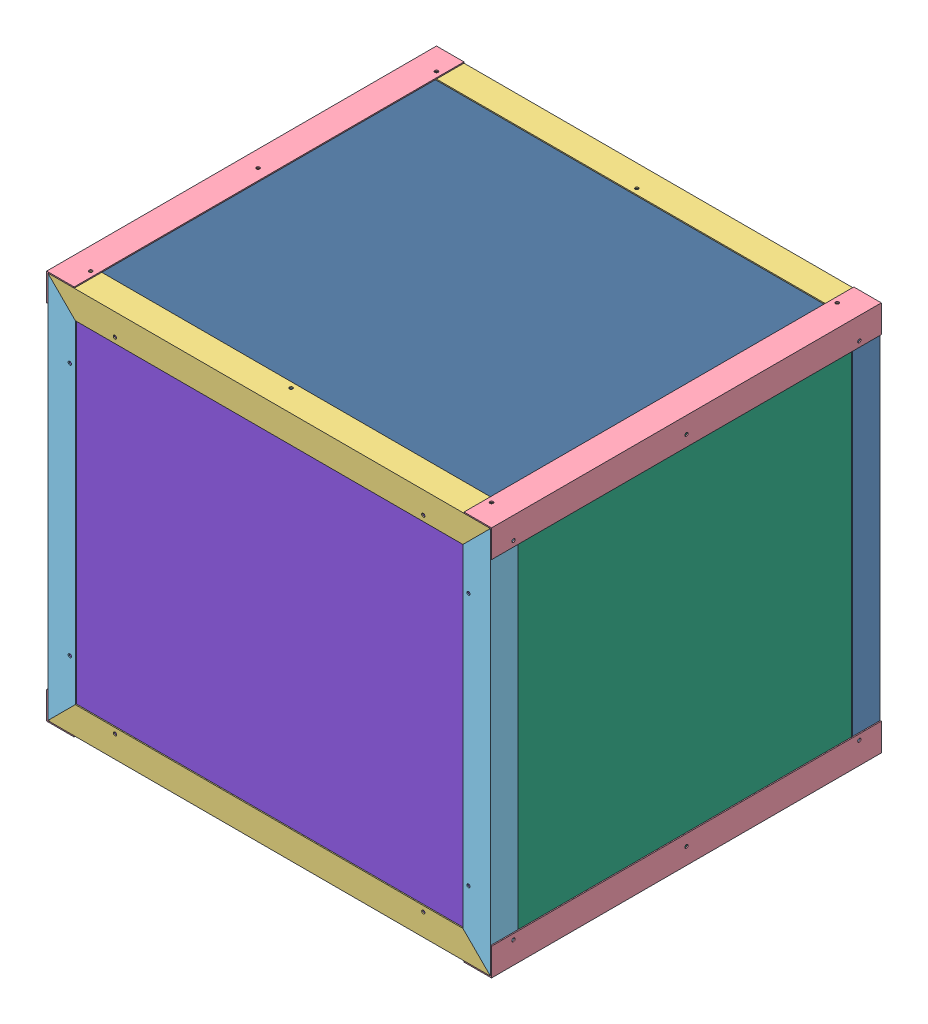
SolidWorks assembly INCUBADORA3.1, configuration Predeterminado. Lengths in mm.
Overall size (404 354 354).
34 component instances, 20 part files, 66 mates.
Components (placement in the parent):
- Soporte_Estructura_vertical_frontalIZQ_35x2.5x0.1-1: Soporte_Estructura_vertical_frontalIZQ_35x2.5x0.1 [Predeterminado] at (-68.7256 99.4418 337.5001) size (25 350 25)
- Soporte_Estructura_vertical_frontalDER_35x2.5x0.1-1: Soporte_Estructura_vertical_frontalDER_35x2.5x0.1 [Predeterminado] at (-579.6091 -128.1974 337.5001) x (-1 0 0) z (0 0 1) size (25 350 25)
- Soporte_Estructura_Horizontal_40x2.5x0.1-1: Soporte_Estructura_Horizontal_40x2.5x0.1 [Predeterminado] at (-416.987 216.064 337.5001) x (0 1 0) z (0 0 1) size (25 400 25)
- Soporte_Estructura_Horizontal_40x2.5x0.1-2: Soporte_Estructura_Horizontal_40x2.5x0.1 [Predeterminado] at (-231.3477 -244.8196 337.5001) x (0 -1 0) z (0 0 1) size (25 400 25)
- Soporte_Estructura_Esquinas_35.4x2.5x0.1-1: Soporte_Estructura_Esquinas_35.4x2.5x0.1 [Predeterminado] at (-66.9091 162.6222 626.3194) x (1 0 0) z (0 -1 0) size (25 354 25)
- Soporte_Estructura_Esquinas_35.4x2.5x0.1-2: Soporte_Estructura_Esquinas_35.4x2.5x0.1 [Predeterminado] at (-526.1674 217.8804 626.3194) x (0 1 0) z (1 0 0) size (25 354 25)
- Soporte_Estructura_Esquinas_35.4x2.5x0.1-3: Soporte_Estructura_Esquinas_35.4x2.5x0.1 [Predeterminado] at (-66.9091 -191.3778 402.6808) x (1 0 0) z (0 1 0) size (25 354 25)
- Soporte_Estructura_Esquinas_35.4x2.5x0.1-4: Soporte_Estructura_Esquinas_35.4x2.5x0.1 [Predeterminado] at (-581.4256 -191.3778 626.3194) x (-1 0 0) z (0 1 0) size (25 354 25)
- Soporte_Estructura_vertica_35x2.5x0.1-1: Soporte_Estructura_vertica_35x2.5x0.1 [Predeterminado] at (-579.6091 99.4418 691.5001) x (-1 0 0) z (0 0 -1) size (25 350 25)
- Soporte_Estructura_Horizontal_40x2.5x0.1-3: Soporte_Estructura_Horizontal_40x2.5x0.1 [Predeterminado] at (-231.3477 216.064 691.5001) x (0 1 0) z (0 0 -1) size (25 400 25)
- Soporte_Estructura_vertica_35x2.5x0.1-2: Soporte_Estructura_vertica_35x2.5x0.1 [Predeterminado] at (-68.7256 -128.1974 691.5001) x (1 0 0) z (0 0 -1) size (25 350 25)
- Soporte_Estructura_Horizontal_40x2.5x0.1-4: Soporte_Estructura_Horizontal_40x2.5x0.1 [Predeterminado] at (-416.987 -244.8196 691.5001) x (0 -1 0) z (0 0 -1) size (25 400 25)
- PVC_34x34x0.5-1: PVC_34x34x0.5 [Predeterminado] at (-524.1674 106.0862 623.4473) x (0 0 -1) z (1 0 0) size (340 340 5)
- PVC_34x34x0.5-2: PVC_34x34x0.5 [Predeterminado] at (-129.1674 106.0862 623.4473) x (0 0 -1) z (1 0 0) size (340 340 5)
- PVC_15x39x0.5-1: PVC_15x39x0.5 [Predeterminado] at (-454.5461 96.675 338.5001) x (0 1 0) z (0 0 1) size (120 390 5)
- PVC_FONDO_34x39x0.5-1: PVC_FONDO_34x39x0.5 [Predeterminado] at (-178.7034 94.5694 685.5001) x (0 -1 0) z (0 0 1) size (340 390 5)
- Soporte_Estructura_vertical_central-IZQ_35x2.5x0.1-1: Soporte_Estructura_vertical_central-IZQ_35x2.5x0.1 [Predeterminado] at (-73.8274 99.4418 502.0001) size (25 352 25)
- PVC_34x39x0.5-4: PVC_34x39x0.5 [Predeterminado] at (-178.7034 160.6222 576.1027) x (0 0 -1) z (0 -1 0) size (340 390 5)
- Soporte_Estructura_vertical_central-DER_35x2.5x0.1-2: Soporte_Estructura_vertical_central-DER_35x2.5x0.1 [Predeterminado] at (-574.5074 -128.1974 502.0001) x (-1 0 0) z (0 0 1) size (25 352 25)
- PVC_34x39x0.5-5: PVC_34x39x0.5 [Predeterminado] at (-469.6313 -189.3778 576.1027) x (0 0 -1) z (0 1 0) size (340 390 5)
- Powder Coating Oven Light Unit-1: Powder Coating Oven Light Unit [Default] at (-335.8979 98.7262 682.5791) x (-1 0 0) z (0 -1 0) size (113.79 123.2 113.79)
  - Porcelain Lampholder Light Fixture-1: Porcelain Lampholder Light Fixture [Default] at origin size (113.79 41.16 113.79)
  - Light Bulb-1: Light Bulb [Default] at (0 12.954 0) x (0.978795 0 0.204841) z (-0.204841 0 0.978795) size (60.2 107.19 60.2)
- Bandeja_Huevos_27x36x2.5-1: Bandeja_Huevos_27x36x2.5 [Predeterminado] at (-320.2845 -467.3185 590.677) x (0 -0.439591 -0.898198) z (0 0.898198 -0.439591) size (272 362 29)
  - Soporte_Bandeja_Horizonta_40x2.5x0.1-1: Soporte_Bandeja_Horizonta_40x2.5x0.1 [Predeterminado] at (53.9361 154.3977 387.5) size (25 360 25)
  - Soporte_Bandeja_Horizonta_40x2.5x0.1-4: Soporte_Bandeja_Horizonta_40x2.5x0.1 [Predeterminado] at (-274.8673 -152.6319 387.5) x (-1 0 0) z (0 0 1) size (25 360 25)
  - Soporte_Bandeja_Vertical_27x2.5x0.1-2: Soporte_Bandeja_Vertical_27x2.5x0.1 [Predeterminado] at (-218.9804 210.2846 386.5) x (0 1 0) z (0 0 1) size (25 270 25)
  - Soporte_Bandeja_Vertical_27x2.5x0.1-3: Soporte_Bandeja_Vertical_27x2.5x0.1 [Predeterminado] at (-1.9508 -208.5189 386.5) x (0 -1 0) z (0 0 1) size (25 270 25)
  - Bandeja_Down_27x36x0.5-1: Bandeja_Down_27x36x0.5 [Predeterminado] at (-199.9841 -101.0844 388.5) x (0 1 0) z (0 0 1) size (350 260 3)
  - Bandeja_Up_27x36x0.3-1: Bandeja_Up_27x36x0.3 [Predeterminado] at (-20.9471 102.8502 412.5) x (0 -1 0) z (0 0 1) size (360 270 3)
- fan-1: fan [Default] at (-334.2663 115.6222 522.7811) x (1 0 0) z (0 -1 0) size (80 25.5 80)
  - stator-1: stator [Default] at origin size (80 25.5 80)
  - rotor-1: rotor [Default] at (0 2.5 0) x (0.997026 0 -0.077067) z (0.077067 0 0.997026) size (70 23.35 70)
- 20X4LCD JHD204A-1: 20X4LCD JHD204A [Default] at (-419.5674 97.6222 346.8001) x (1 0 0) z (0 1 0) size (98.3 9.76 60)
Mates (geometry in assembly coordinates):
- Coincidente1: coincident anti-aligned: plane of Soporte_Estructura_vertical_frontalIZQ_35x2.5x0.1-1 through (-124.1674 160.6222 338.5001) normal (-0.707107 0.707107 0); plane of Soporte_Estructura_Horizontal_40x2.5x0.1-1 through (-124.1674 160.6222 338.5001) normal (0.707107 -0.707107 0)
- Coincidente2: coincident aligned: plane of Soporte_Estructura_vertical_frontalIZQ_35x2.5x0.1-1 through (-68.7256 99.4418 337.5001) normal (0 0 -1); plane of Soporte_Estructura_Horizontal_40x2.5x0.1-1 through (-416.987 216.064 337.5001) normal (0 0 -1)
- Coincidente3: coincident aligned: line of Soporte_Estructura_vertical_frontalIZQ_35x2.5x0.1-1 through (-124.1674 160.6222 362.5001) axis (0 0 -1); line of Soporte_Estructura_Horizontal_40x2.5x0.1-1 through (-124.1674 160.6222 362.5001) axis (0 0 -1)
- Coincidente4: coincident anti-aligned: plane of Soporte_Estructura_vertical_frontalDER_35x2.5x0.1-1 through (-524.1674 160.6222 338.5001) normal (0.707107 0.707107 0); plane of Soporte_Estructura_Horizontal_40x2.5x0.1-1 through (-524.1674 160.6222 338.5001) normal (-0.707107 -0.707107 0)
- Coincidente5: coincident aligned: plane of Soporte_Estructura_vertical_frontalDER_35x2.5x0.1-1 through (-579.6091 -128.1974 337.5001) normal (0 0 -1); plane of Soporte_Estructura_Horizontal_40x2.5x0.1-1 through (-416.987 216.064 337.5001) normal (0 0 -1)
- Coincidente6: coincident aligned: line of Soporte_Estructura_vertical_frontalDER_35x2.5x0.1-1 through (-524.1674 160.6222 362.5001) axis (0 0 -1); line of Soporte_Estructura_Horizontal_40x2.5x0.1-1 through (-524.1674 160.6222 362.5001) axis (0 0 -1)
- Coincidente7: coincident anti-aligned: plane of Soporte_Estructura_vertical_frontalDER_35x2.5x0.1-1 through (-524.1674 -189.3778 338.5001) normal (0.707107 -0.707107 0); plane of Soporte_Estructura_Horizontal_40x2.5x0.1-2 through (-524.1674 -189.3778 338.5001) normal (-0.707107 0.707107 0)
- Coincidente8: coincident aligned: plane of Soporte_Estructura_vertical_frontalDER_35x2.5x0.1-1 through (-579.6091 -128.1974 337.5001) normal (0 0 -1); plane of Soporte_Estructura_Horizontal_40x2.5x0.1-2 through (-231.3477 -244.8196 337.5001) normal (0 0 -1)
- Coincidente9: coincident aligned: line of Soporte_Estructura_vertical_frontalDER_35x2.5x0.1-1 through (-524.1674 -189.3778 362.5001) axis (0 0 -1); line of Soporte_Estructura_Horizontal_40x2.5x0.1-2 through (-524.1674 -189.3778 362.5001) axis (0 0 -1)
- Coincidente10: coincident anti-aligned: plane of Soporte_Estructura_Horizontal_40x2.5x0.1-1 through (-524.1674 161.6222 362.5001) normal (0 1 0); plane of Soporte_Estructura_Esquinas_35.4x2.5x0.1-1 through (-66.9091 161.6222 626.3194) normal (0 -1 0)
- Coincidente11: coincident anti-aligned: plane of Soporte_Estructura_vertical_frontalIZQ_35x2.5x0.1-1 through (-123.1674 160.6222 362.5001) normal (1 0 0); plane of Soporte_Estructura_Esquinas_35.4x2.5x0.1-1 through (-123.1674 137.6222 691.5001) normal (-1 0 0)
- Coincidente12: coincident aligned: plane of Soporte_Estructura_vertical_frontalIZQ_35x2.5x0.1-1 through (-68.7256 99.4418 337.5001) normal (0 0 -1); plane of Soporte_Estructura_Esquinas_35.4x2.5x0.1-1 through (-123.1674 137.6222 337.5001) normal (0 0 -1)
- Coincidente13: coincident anti-aligned: plane of Soporte_Estructura_Horizontal_40x2.5x0.1-1 through (-524.1674 161.6222 362.5001) normal (0 1 0); plane of Soporte_Estructura_Esquinas_35.4x2.5x0.1-2 through (-501.1674 161.6222 691.5001) normal (0 -1 0)
- Coincidente14: coincident anti-aligned: plane of Soporte_Estructura_vertical_frontalDER_35x2.5x0.1-1 through (-525.1674 -189.3778 362.5001) normal (-1 0 0); plane of Soporte_Estructura_Esquinas_35.4x2.5x0.1-2 through (-525.1674 217.8804 626.3194) normal (1 0 0)
- Coincidente16: coincident aligned: plane of Soporte_Estructura_Horizontal_40x2.5x0.1-1 through (-416.987 216.064 337.5001) normal (0 0 -1); plane of Soporte_Estructura_Esquinas_35.4x2.5x0.1-2 through (-501.1674 161.6222 337.5001) normal (0 0 -1)
- Coincidente17: coincident anti-aligned: plane of Soporte_Estructura_Horizontal_40x2.5x0.1-2 through (-124.1674 -190.3778 362.5001) normal (0 -1 0); plane of Soporte_Estructura_Esquinas_35.4x2.5x0.1-3 through (-66.9091 -190.3778 402.6808) normal (0 1 0)
- Coincidente19: coincident anti-aligned: plane of Soporte_Estructura_vertical_frontalIZQ_35x2.5x0.1-1 through (-123.1674 160.6222 362.5001) normal (1 0 0); plane of Soporte_Estructura_Esquinas_35.4x2.5x0.1-3 through (-123.1674 -166.3778 337.5001) normal (-1 0 0)
- Coincidente20: coincident aligned: plane of Soporte_Estructura_vertical_frontalIZQ_35x2.5x0.1-1 through (-68.7256 99.4418 337.5001) normal (0 0 -1); plane of Soporte_Estructura_Esquinas_35.4x2.5x0.1-3 through (-123.1674 -166.3778 337.5001) normal (0 0 -1)
- Coincidente21: coincident anti-aligned: plane of Soporte_Estructura_Horizontal_40x2.5x0.1-2 through (-124.1674 -190.3778 362.5001) normal (0 -1 0); plane of Soporte_Estructura_Esquinas_35.4x2.5x0.1-4 through (-581.4256 -190.3778 626.3194) normal (0 1 0)
- Coincidente22: coincident anti-aligned: plane of Soporte_Estructura_vertical_frontalDER_35x2.5x0.1-1 through (-525.1674 -189.3778 362.5001) normal (-1 0 0); plane of Soporte_Estructura_Esquinas_35.4x2.5x0.1-4 through (-525.1674 -166.3778 691.5001) normal (1 0 0)
- Coincidente23: coincident aligned: plane of Soporte_Estructura_vertical_frontalDER_35x2.5x0.1-1 through (-579.6091 -128.1974 337.5001) normal (0 0 -1); plane of Soporte_Estructura_Esquinas_35.4x2.5x0.1-4 through (-525.1674 -166.3778 337.5001) normal (0 0 -1)
- Coincidente24: coincident anti-aligned: plane of Soporte_Estructura_Esquinas_35.4x2.5x0.1-2 through (-525.1674 217.8804 626.3194) normal (1 0 0); plane of Soporte_Estructura_vertica_35x2.5x0.1-1 through (-525.1674 160.6222 666.5001) normal (-1 0 0)
- Coincidente25: coincident aligned: plane of Soporte_Estructura_Esquinas_35.4x2.5x0.1-2 through (-501.1674 161.6222 691.5001) normal (0 0 1); plane of Soporte_Estructura_vertica_35x2.5x0.1-1 through (-579.6091 99.4418 691.5001) normal (0 0 1)
- Coincidente27: coincident anti-aligned: plane of Soporte_Estructura_Esquinas_35.4x2.5x0.1-2 through (-501.1674 161.6222 691.5001) normal (0 -1 0); plane of Soporte_Estructura_Horizontal_40x2.5x0.1-3 through (-124.1674 161.6222 666.5001) normal (0 1 0)
- Coincidente28: coincident aligned: plane of Soporte_Estructura_vertica_35x2.5x0.1-1 through (-579.6091 99.4418 691.5001) normal (0 0 1); plane of Soporte_Estructura_Horizontal_40x2.5x0.1-3 through (-231.3477 216.064 691.5001) normal (0 0 1)
- Coincidente29: coincident anti-aligned: plane of Soporte_Estructura_vertica_35x2.5x0.1-1 through (-524.1674 160.6222 690.5001) normal (0.707107 0.707107 0); plane of Soporte_Estructura_Horizontal_40x2.5x0.1-3 through (-524.1674 160.6222 690.5001) normal (-0.707107 -0.707107 0)
- Coincidente30: coincident aligned: plane of Soporte_Estructura_Horizontal_40x2.5x0.1-3 through (-231.3477 216.064 691.5001) normal (0 0 1); plane of Soporte_Estructura_vertica_35x2.5x0.1-2 through (-68.7256 -128.1974 691.5001) normal (0 0 1)
- Coincidente31: coincident anti-aligned: plane of Soporte_Estructura_Esquinas_35.4x2.5x0.1-1 through (-123.1674 137.6222 691.5001) normal (-1 0 0); plane of Soporte_Estructura_vertica_35x2.5x0.1-2 through (-123.1674 -189.3778 666.5001) normal (1 0 0)
- Coincidente32: coincident anti-aligned: plane of Soporte_Estructura_Horizontal_40x2.5x0.1-3 through (-124.1674 160.6222 690.5001) normal (0.707107 -0.707107 0); plane of Soporte_Estructura_vertica_35x2.5x0.1-2 through (-124.1674 160.6222 690.5001) normal (-0.707107 0.707107 0)
- Coincidente33: coincident aligned: plane of Soporte_Estructura_vertica_35x2.5x0.1-2 through (-68.7256 -128.1974 691.5001) normal (0 0 1); plane of Soporte_Estructura_Horizontal_40x2.5x0.1-4 through (-416.987 -244.8196 691.5001) normal (0 0 1)
- Coincidente34: coincident anti-aligned: plane of Soporte_Estructura_Esquinas_35.4x2.5x0.1-4 through (-581.4256 -190.3778 626.3194) normal (0 1 0); plane of Soporte_Estructura_Horizontal_40x2.5x0.1-4 through (-524.1674 -190.3778 666.5001) normal (0 -1 0)
- Coincidente35: coincident anti-aligned: plane of Soporte_Estructura_vertica_35x2.5x0.1-2 through (-124.1674 -189.3778 690.5001) normal (-0.707107 -0.707107 0); plane of Soporte_Estructura_Horizontal_40x2.5x0.1-4 through (-124.1674 -189.3778 690.5001) normal (0.707107 0.707107 0)
- Coincidente36: coincident: moEndPointRef_w of Soporte_Estructura_vertica_35x2.5x0.1-2; moEndPointRef_w of Soporte_Estructura_Horizontal_40x2.5x0.1-4
- Coincidente40: coincident anti-aligned: plane of Soporte_Estructura_vertica_35x2.5x0.1-1 through (-524.1674 160.6222 666.5001) normal (1 0 0); plane of PVC_34x34x0.5-1 through (-524.1674 106.0862 623.4473) normal (-1 0 0)
- Distancia3: distance = 6 mm anti-aligned: plane of PVC_34x34x0.5-1 through (-519.1674 155.6222 344.5001) normal (0 0 -1); plane of Soporte_Estructura_vertical_frontalDER_35x2.5x0.1-1 through (-579.6091 -128.1974 338.5001) normal (0 0 1)
- Distancia4: distance = 5 mm anti-aligned: plane of Soporte_Estructura_Horizontal_40x2.5x0.1-1 through (-524.1674 160.6222 362.5001) normal (0 -1 0); plane of PVC_34x34x0.5-1 through (-519.1674 155.6222 684.5001) normal (0 1 0)
- Coincidente48: coincident anti-aligned: plane of Soporte_Estructura_vertica_35x2.5x0.1-2 through (-124.1674 -189.3778 666.5001) normal (-1 0 0); plane of PVC_34x34x0.5-2 through (-124.1674 106.0862 623.4473) normal (1 0 0)
- Distancia8: distance = 6 mm anti-aligned: plane of Soporte_Estructura_vertica_35x2.5x0.1-2 through (-68.7256 -128.1974 690.5001) normal (0 0 -1); plane of PVC_34x34x0.5-2 through (-124.1674 155.6222 684.5001) normal (0 0 1)
- Distancia9: distance = 6 mm anti-aligned: plane of PVC_34x34x0.5-2 through (-124.1674 -184.3778 684.5001) normal (0 -1 0); plane of Soporte_Estructura_Esquinas_35.4x2.5x0.1-3 through (-66.9091 -190.3778 402.6808) normal (0 1 0)
- Distancia11: distance = 5 mm anti-aligned: plane of Soporte_Estructura_vertical_frontalDER_35x2.5x0.1-1 through (-524.1674 -189.3778 362.5001) normal (1 0 0); plane of PVC_15x39x0.5-1 through (-519.1674 35.6222 343.5001) normal (-1 0 0)
- Distancia10: distance = 5 mm anti-aligned: plane of PVC_15x39x0.5-1 through (-519.1674 155.6222 343.5001) normal (0 1 0); plane of Soporte_Estructura_Horizontal_40x2.5x0.1-1 through (-524.1674 160.6222 362.5001) normal (0 -1 0)
- Coincidente53: coincident anti-aligned: plane of Soporte_Estructura_vertical_frontalDER_35x2.5x0.1-1 through (-579.6091 -128.1974 338.5001) normal (0 0 1); plane of PVC_15x39x0.5-1 through (-454.5461 96.675 338.5001) normal (0 0 -1)
- Coincidente54: coincident anti-aligned: plane of Soporte_Estructura_vertica_35x2.5x0.1-2 through (-68.7256 -128.1974 690.5001) normal (0 0 -1); plane of PVC_FONDO_34x39x0.5-1 through (-178.7034 94.5694 690.5001) normal (0 0 1)
- Distancia12: distance = 5 mm anti-aligned: plane of PVC_FONDO_34x39x0.5-1 through (-129.1674 155.6222 690.5001) normal (1 0 0); plane of Soporte_Estructura_vertica_35x2.5x0.1-2 through (-124.1674 -189.3778 666.5001) normal (-1 0 0)
- Distancia13: distance = 5 mm anti-aligned: plane of Soporte_Estructura_Horizontal_40x2.5x0.1-3 through (-124.1674 160.6222 666.5001) normal (0 -1 0); plane of PVC_FONDO_34x39x0.5-1 through (-129.1674 155.6222 690.5001) normal (0 1 0)
- Coincidente57: coincident anti-aligned: plane of PVC_34x34x0.5-2 through (-129.1674 106.0862 623.4473) normal (-1 0 0); plane of Soporte_Estructura_vertical_central-IZQ_35x2.5x0.1-1 through (-129.1674 161.6222 527.0001) normal (1 0 0)
- Coincidente58: coincident anti-aligned: plane of Soporte_Estructura_Esquinas_35.4x2.5x0.1-3 through (-66.9091 -190.3778 402.6808) normal (0 1 0); plane of Soporte_Estructura_vertical_central-IZQ_35x2.5x0.1-1 through (-130.1674 -190.3778 527.0001) normal (0 -1 0)
- Coincidente59: coincident anti-aligned: plane of Soporte_Estructura_Horizontal_40x2.5x0.1-1 through (-524.1674 160.6222 362.5001) normal (0 -1 0); plane of PVC_34x39x0.5-4 through (-178.7034 160.6222 576.1027) normal (0 1 0)
- Distancia15: distance = 5 mm anti-aligned: plane of Soporte_Estructura_vertical_frontalDER_35x2.5x0.1-1 through (-524.1674 -189.3778 362.5001) normal (1 0 0); plane of PVC_34x39x0.5-4 through (-519.1674 155.6222 499.5001) normal (-1 0 0)
- Distancia16: distance = 6 mm anti-aligned: plane of Soporte_Estructura_Horizontal_40x2.5x0.1-1 through (-416.987 216.064 338.5001) normal (0 0 1); plane of PVC_34x39x0.5-4 through (-129.1674 155.6222 344.5001) normal (0 0 -1)
- Coincidente63: coincident anti-aligned: plane of PVC_34x34x0.5-1 through (-519.1674 106.0862 623.4473) normal (1 0 0); plane of Soporte_Estructura_vertical_central-DER_35x2.5x0.1-2 through (-519.1674 -190.3778 527.0001) normal (-1 0 0)
- Coincidente64: coincident anti-aligned: plane of Soporte_Estructura_Esquinas_35.4x2.5x0.1-2 through (-501.1674 161.6222 691.5001) normal (0 -1 0); plane of Soporte_Estructura_vertical_central-DER_35x2.5x0.1-2 through (-518.1674 161.6222 527.0001) normal (0 1 0)
- Coincidente65: coincident anti-aligned: plane of Soporte_Estructura_Horizontal_40x2.5x0.1-4 through (-524.1674 -189.3778 666.5001) normal (0 1 0); plane of PVC_34x39x0.5-5 through (-469.6313 -189.3778 576.1027) normal (0 -1 0)
- Distancia17: distance = 5 mm anti-aligned: plane of Soporte_Estructura_vertica_35x2.5x0.1-2 through (-124.1674 -189.3778 666.5001) normal (-1 0 0); plane of PVC_34x39x0.5-5 through (-129.1674 -184.3778 684.5001) normal (1 0 0)
- Distancia18: distance = 6 mm anti-aligned: plane of PVC_34x39x0.5-5 through (-519.1674 -184.3778 344.5001) normal (0 0 -1); plane of Soporte_Estructura_Horizontal_40x2.5x0.1-2 through (-231.3477 -244.8196 338.5001) normal (0 0 1)
- Concéntrica2: concentric aligned: cylinder of Soporte_Estructura_vertical_central-DER_35x2.5x0.1-2 through (-518.1674 -60.3778 514.5001) axis (-1 0 0) radius 5; cylinder of Bandeja_Huevos_27x36x2.5-1/Soporte_Bandeja_Vertical_27x2.5x0.1-2 through (-501.1674 -60.3778 514.5001) axis (-1 0 0) radius 5
- Distancia20: distance = 163.5 mm anti-aligned: plane of Soporte_Estructura_vertical_central-IZQ_35x2.5x0.1-1 through (-73.8274 99.4418 502.0001) normal (0 0 -1); plane of Soporte_Estructura_vertical_frontalIZQ_35x2.5x0.1-1 through (-68.7256 99.4418 338.5001) normal (0 0 1)
- Distancia21: distance = 163.5 mm anti-aligned: plane of Soporte_Estructura_vertical_frontalDER_35x2.5x0.1-1 through (-579.6091 -128.1974 338.5001) normal (0 0 1); plane of Soporte_Estructura_vertical_central-DER_35x2.5x0.1-2 through (-574.5074 -128.1974 502.0001) normal (0 0 -1)
- Ángulo límite1: limit planar angle = 3.596736 rad aligned: line of Bandeja_Huevos_27x36x2.5-1/Soporte_Bandeja_Vertical_27x2.5x0.1-3 through (-140.1674 -12.2605 641.2517) axis (0 -0.439591 -0.898198); line of Soporte_Estructura_Esquinas_35.4x2.5x0.1-3 through (-123.1674 -166.3778 337.5001) axis (0 0 1)
- Distancia22: distance = 10 mm anti-aligned: plane of Bandeja_Huevos_27x36x2.5-1/Soporte_Bandeja_Vertical_27x2.5x0.1-3 through (-140.1674 -108.4951 387.7485) normal (1 0 0); plane of Soporte_Estructura_vertical_central-IZQ_35x2.5x0.1-1 through (-130.1674 161.6222 527.0001) normal (-1 0 0)
- Coincidente66: coincident anti-aligned: plane of PVC_FONDO_34x39x0.5-1 through (-178.7034 94.5694 685.5001) normal (0 0 -1); plane of Powder Coating Oven Light Unit-1/Porcelain Lampholder Light Fixture-1 through (-348.0511 111.9377 685.5001) normal (0 0 1)
- Tangente1: tangent anti-aligned: plane of PVC_34x39x0.5-4 through (-178.7034 155.6222 576.1027) normal (0 -1 0); cylinder of Powder Coating Oven Light Unit-1/Porcelain Lampholder Light Fixture-1 through (-335.8979 98.7262 682.5791) axis (0 0 1) radius 56.896
- Coincidente67: coincident anti-aligned: plane of PVC_34x39x0.5-4 through (-178.7034 155.6222 576.1027) normal (0 -1 0); plane of fan-1/stator-1 through (-374.2663 155.6222 548.2811) normal (0 1 0)
- Coincidente68: coincident aligned: plane of PVC_15x39x0.5-1 through (-454.5461 96.675 338.5001) normal (0 0 -1); plane of 20X4LCD JHD204A-1 through (-509.2858 97.6222 338.5001) normal (0 0 -1)
- Distancia23: distance = 2.5 mm anti-aligned: plane of PVC_15x39x0.5-1 through (-369.1674 75.6222 343.5001) normal (0 1 0); plane of 20X4LCD JHD204A-1 through (-509.2858 78.1222 338.5001) normal (0 -1 0)
- Distancia24: distance = 2.5 mm anti-aligned: plane of PVC_15x39x0.5-1 through (-369.1674 75.6222 343.5001) normal (-1 0 0); plane of 20X4LCD JHD204A-1 through (-371.6674 97.6222 338.5001) normal (1 0 0)
